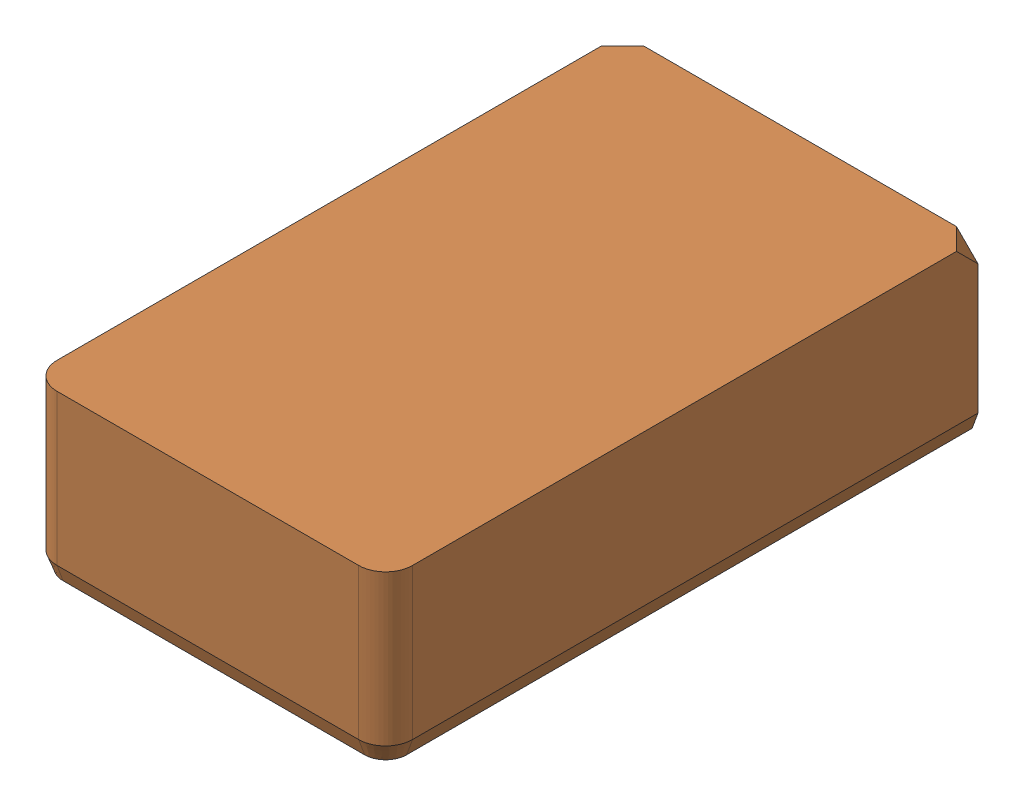
SolidWorks assembly carcasa, configuration Predeterminado. Lengths in mm.
Overall size (66 31 111.98).
2 component instances, 2 part files, 3 mates.
Components (placement in the parent):
- base-2: base [Predeterminado] x (-1 0 0) z (0 0 -1) size (55 28 105)
- tapa-1: tapa [Predeterminado] at (0 25 4.4762) x (-1 0 0) z (0 0 -1) size (66 31 110)
Mates (geometry in assembly coordinates):
- Paralelo1: parallel anti-aligned: plane of base-2 through (25.5 0 0) normal (1 0 0); plane of tapa-1 through (26 25 4.4762) normal (-1 0 0)
- Coincidente3: coincident anti-aligned: plane of base-2 through (25.5 5 -52.5) normal (0 -1 0); plane of tapa-1 through (26 5 -50.5238) normal (0 1 0)
- Distancia1: distance = 0.5 mm anti-aligned: plane of base-2 through (25.5 0 0) normal (1 0 0); plane of tapa-1 through (26 25 4.4762) normal (-1 0 0)
